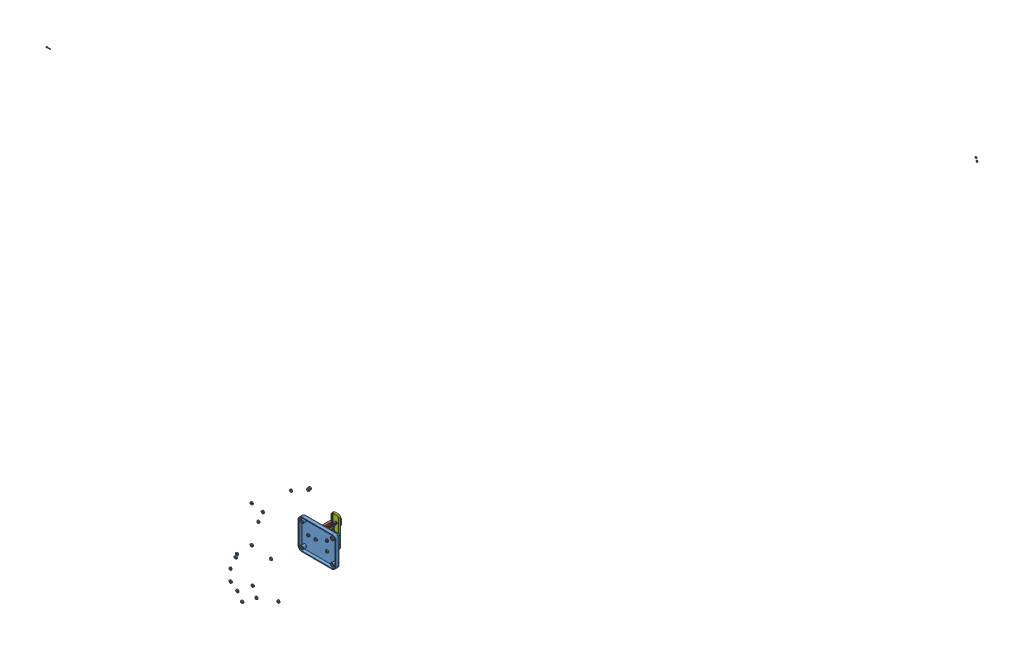
SolidWorks assembly motion_study, configuration Default. Lengths in mm.
Overall size (1399.7 805.72 1298.1).
38 component instances, 9 part files, 40 mates.
Components (placement in the parent):
- base-1: base [Default] at (50.4924 43.8567 70.47) size (100 80 10)
- bracket-1: bracket [Default] at (30.4924 43.8567 70.47) x (-1 0 0) z (0 0 -1) size (36 36 73)
- servo_mount-1: servo_mount [Default] at (52.4924 43.8567 70.47) x (1 0 0) z (0 1 0) size (30 30 36)
- socket head cap screw_ai-3: socket head cap screw_ai [HX-SHCS 0.112-40x0.375x0.375-N] at (20.4924 43.8567 64.6252) x (0 0 1) z (0.812322 -0.583209 0) size (12.37 4.65 4.65)
- socket head cap screw_ai-4: socket head cap screw_ai [HX-SHCS 0.112-40x0.375x0.375-N] at (40.4924 43.8567 64.6252) x (0 0 1) z (-0.967411 -0.25321 0) size (12.37 4.65 4.65)
- socket head cap screw_ai-18: socket head cap screw_ai [HX-SHCS 0.112-40x0.375x0.375-N] at (70.4924 56.3567 64.6252) x (0 0 1) z (-0.695922 0.718118 0) size (12.37 4.65 4.65)
- socket head cap screw_ai-19: socket head cap screw_ai [HX-SHCS 0.112-40x0.375x0.375-N] at (22.6476 43.6627 23.1238) x (1 0 0) z (0 0.590305 0.80718) size (12.37 4.65 4.65)
- socket head cap screw_ai-20: socket head cap screw_ai [HX-SHCS 0.112-40x0.375x0.375-N] at (70.4924 31.3567 64.6252) x (0 0 1) z (0.03914 0.999234 0) size (12.37 4.65 4.65)
- machine screw nut hex_ai-2: machine screw nut hex_ai [MSHXNUT 0.112-40-S-N] at (21.6751 -68.2967 155.3337) size (6.35 7.33 2.49)
- machine screw nut hex_ai-3: machine screw nut hex_ai [MSHXNUT 0.112-40-S-N] at (-36.4584 -88.814 155.5393) size (6.35 7.33 2.49)
- machine screw nut hex_ai-4: machine screw nut hex_ai [MSHXNUT 0.112-40-S-N] at (-64.4617 -107.1752 165.356) size (6.35 7.33 2.49)
- machine screw nut hex_ai-5: machine screw nut hex_ai [MSHXNUT 0.112-40-S-N] at (-92.7843 -103.8393 150.1747) size (6.35 7.33 2.49)
- machine screw nut hex_ai-6: machine screw nut hex_ai [MSHXNUT 0.112-40-S-N] at (-123.0762 -103.4925 137.6299) size (6.35 7.33 2.49)
- machine screw nut hex_ai-7: machine screw nut hex_ai [MSHXNUT 0.112-40-S-N] at (-142.6432 -93.4426 118.2638) size (6.35 7.33 2.49)
- machine screw nut hex_ai-8: machine screw nut hex_ai [MSHXNUT 0.112-40-S-N] at (-147.3644 -78.9178 99.7217) size (6.35 7.33 2.49)
- machine screw nut hex_ai-9: machine screw nut hex_ai [MSHXNUT 0.112-40-S-N] at (-149.2394 -74.9915 94.4694) size (6.35 7.33 2.49)
- machine screw nut hex_ai-11: machine screw nut hex_ai [MSHXNUT 0.112-40-S-N] at (-182.4764 -10.2892 22.3721) size (6.35 7.33 2.49)
- machine screw nut hex_ai-13: machine screw nut hex_ai [MSHXNUT 0.112-40-S-N] at (20.4924 43.8567 74.9592) size (6.35 7.33 2.49)
- machine screw nut hex_ai-17: machine screw nut hex_ai [MSHXNUT 0.112-40-S-N] at (70.4924 56.3567 74.9338) size (6.35 7.33 2.49)
- machine screw nut hex_ai-18: machine screw nut hex_ai [MSHXNUT 0.112-40-S-N] at (-74.3839 54.9241 -24.4269) size (6.35 7.33 2.49)
- machine screw nut hex_ai-19: machine screw nut hex_ai [MSHXNUT 0.112-40-S-N] at (40.4924 43.8567 74.9592) size (6.35 7.33 2.49)
- machine screw nut hex_ai-20: machine screw nut hex_ai [MSHXNUT 0.112-40-S-N] at (-75.8204 52.0566 -21.7162) size (6.35 7.33 2.49)
- machine screw nut hex_ai-21: machine screw nut hex_ai [MSHXNUT 0.112-40-S-N] at (70.4924 31.3567 74.9592) size (6.35 7.33 2.49)
- machine screw nut hex_ai-22: machine screw nut hex_ai [MSHXNUT 0.112-40-S-N] at (-115.6581 32.8101 -15.6303) size (6.35 7.33 2.49)
- machine screw nut hex_ai-23: machine screw nut hex_ai [MSHXNUT 0.112-40-S-N] at (-151.0091 -14.0767 23.9369) size (6.35 7.33 2.49)
- machine screw nut hex_ai-24: machine screw nut hex_ai [MSHXNUT 0.112-40-S-N] at (-146.959 -26.5776 39.89) size (6.35 7.33 2.49)
- machine screw nut hex_ai-25: machine screw nut hex_ai [MSHXNUT 0.112-40-S-N] at (-127.4649 -52.2459 77.1292) size (6.35 7.33 2.49)
- machine screw nut hex_ai-26: machine screw nut hex_ai [MSHXNUT 0.112-40-S-N] at (-63.8542 -83.0897 137.992) size (6.35 7.33 2.49)
- machine screw nut hex_ai-27: machine screw nut hex_ai [MSHXNUT 0.112-40-S-N] at (-60.5334 -42.4208 92.7075) size (6.35 7.33 2.49)
- Micro Servo FS90R Continuous-1: Micro Servo FS90R Continuous [Valor predeterminado] at (57.4924 43.8567 46.57) x (0 1 0) z (0 0 1) size (32 29 12)
- shelf-1: shelf [Default] at (43.4924 40.0088 25.6238) x (0 -1 0) z (0 0 -1) size (80 26 5)
- servo_arm-1: servo_arm [Default] at (44.9924 49.3667 36.1191) x (0 0.717335 -0.696728) z (-1 0 0) size (38 10 4)
- clip-2: clip [Default] at (25.4924 43.6627 23.1238) x (0 -1 0) z (1 0 0) size (10 7 8)
- socket head cap screw_ai-21: socket head cap screw_ai [HX-SHCS 0.06-80x0.375x0.375-N] at (-803.2469 693.6612 -53.4836) size (11.05 2.44 2.44)
- socket head cap screw_ai-22: socket head cap screw_ai [HX-SHCS 0.06-80x0.375x0.375-N] at (50.9684 57.4817 46.47) x (1 0 0) z (0 0.078665 0.996901) size (11.05 2.44 2.44)
- socket head cap screw_ai-23: socket head cap screw_ai [HX-SHCS 0.06-80x0.375x0.375-N] at (50.9684 30.2317 46.47) size (11.05 2.44 2.44)
- machine screw nut hex_ai-28: machine screw nut hex_ai [MSHXNUT 0.060-80-S-N] at (594.4756 589.4997 -1131.4765) size (3.96 4.58 1.27)
- machine screw nut hex_ai-29: machine screw nut hex_ai [MSHXNUT 0.060-80-S-N] at (592.2475 597.0474 -1131.1006) size (3.96 4.58 1.27)
Mates (geometry in assembly coordinates):
- Coincident1: coincident anti-aligned: plane of base-1 through (50.4924 43.8567 70.47) normal (0 0 -1); plane of bracket-1 through (30.4924 43.8567 70.47) normal (0 0 1)
- Coincident2: coincident anti-aligned: plane of base-1 through (50.4924 43.8567 70.47) normal (0 0 -1); plane of servo_mount-1 through (52.4924 61.8567 70.47) normal (0 0 1)
- Concentric2: concentric aligned: cylinder of servo_mount-1 through (70.4924 56.3567 82.47) axis (0 0 -1) radius 1.5; cylinder of socket head cap screw_ai-18 through (70.4924 56.3567 32.8752) axis (0 0 -1) radius 1.4224
- Concentric3: concentric aligned: cylinder of base-1 through (70.4924 56.3567 80.47) axis (0 0 -1) radius 1.5; cylinder of socket head cap screw_ai-18 through (70.4924 56.3567 32.8752) axis (0 0 -1) radius 1.4224
- Coincident3: coincident aligned: plane of servo_mount-1 through (52.4924 61.8567 67.47) normal (0 0 -1); circle of socket head cap screw_ai-18
- Coincident4: coincident aligned: plane of base-1 through (50.4924 43.8567 72.47) normal (0 0 1); circle of machine screw nut hex_ai-17
- Concentric5: concentric anti-aligned: cylinder of socket head cap screw_ai-18 through (70.4924 56.3567 32.8752) axis (0 0 -1) radius 1.4224; cylinder of machine screw nut hex_ai-17 through (70.4924 56.3567 72.4446) axis (0 0 1) radius 1.1303
- Concentric6: concentric aligned: cylinder of servo_mount-1 through (70.4924 31.3567 82.47) axis (0 0 -1) radius 1.5; cylinder of socket head cap screw_ai-20 through (70.4924 31.3567 32.8752) axis (0 0 -1) radius 1.4224
- Concentric7: concentric aligned: cylinder of base-1 through (70.4924 31.3567 80.47) axis (0 0 -1) radius 1.5; cylinder of socket head cap screw_ai-20 through (70.4924 31.3567 32.8752) axis (0 0 -1) radius 1.4224
- Coincident5: coincident anti-aligned: plane of servo_mount-1 through (52.4924 61.8567 67.47) normal (0 0 -1); plane of socket head cap screw_ai-20 through (72.8147 31.2657 67.47) normal (0 0 1)
- Coincident6: coincident anti-aligned: plane of base-1 through (50.4924 43.8567 72.47) normal (0 0 1); plane of machine screw nut hex_ai-21 through (64.1424 31.3567 72.47) normal (0 0 -1)
- Concentric8: concentric aligned: cylinder of socket head cap screw_ai-20 through (70.4924 31.3567 32.8752) axis (0 0 -1) radius 1.4224; circle of machine screw nut hex_ai-21
- Concentric9: concentric aligned: cylinder of bracket-1 through (40.4924 43.8567 70.47) axis (0 0 -1) radius 1.5; cylinder of socket head cap screw_ai-4 through (40.4924 43.8567 32.8752) axis (0 0 -1) radius 1.4224
- Concentric10: concentric aligned: cylinder of base-1 through (40.4924 43.8567 80.47) axis (0 0 -1) radius 1.5; cylinder of socket head cap screw_ai-4 through (40.4924 43.8567 32.8752) axis (0 0 -1) radius 1.4224
- Coincident7: coincident anti-aligned: plane of bracket-1 through (30.4924 43.8567 67.47) normal (0 0 -1); plane of socket head cap screw_ai-4 through (39.9039 46.105 67.47) normal (0 0 1)
- Concentric11: concentric aligned: cylinder of bracket-1 through (20.4924 43.8567 70.47) axis (0 0 -1) radius 1.5; cylinder of socket head cap screw_ai-3 through (20.4924 43.8567 32.8752) axis (0 0 -1) radius 1.4224
- Concentric12: concentric aligned: cylinder of base-1 through (20.4924 43.8567 80.47) axis (0 0 -1) radius 1.5; cylinder of socket head cap screw_ai-3 through (20.4924 43.8567 32.8752) axis (0 0 -1) radius 1.4224
- Coincident8: coincident anti-aligned: plane of bracket-1 through (30.4924 43.8567 67.47) normal (0 0 -1); plane of socket head cap screw_ai-3 through (19.1369 41.9687 67.47) normal (0 0 1)
- Coincident12: coincident anti-aligned: plane of base-1 through (50.4924 43.8567 72.47) normal (0 0 1); plane of machine screw nut hex_ai-13 through (14.1424 43.8567 72.47) normal (0 0 -1)
- Concentric14: concentric anti-aligned: cylinder of socket head cap screw_ai-3 through (20.4924 43.8567 32.8752) axis (0 0 -1) radius 1.4224; cylinder of machine screw nut hex_ai-13 through (20.4924 43.8567 72.47) axis (0 0 1) radius 1.1303
- Coincident13: coincident anti-aligned: plane of base-1 through (50.4924 43.8567 72.47) normal (0 0 1); circle of machine screw nut hex_ai-19
- Concentric15: concentric anti-aligned: cylinder of socket head cap screw_ai-4 through (40.4924 43.8567 32.8752) axis (0 0 -1) radius 1.4224; cylinder of machine screw nut hex_ai-19 through (40.4924 43.8567 72.47) axis (0 0 1) radius 1.1303
- Coincident14: coincident anti-aligned: plane of servo_mount-1 through (52.4924 55.1067 52.47) normal (0 0 -1); plane of Micro Servo FS90R Continuous-1 through (57.4924 43.8567 52.47) normal (0 0 1)
- Coincident15: coincident anti-aligned: plane of servo_mount-1 through (52.4924 55.1067 52.47) normal (0 -1 0); plane of Micro Servo FS90R Continuous-1 through (73.4924 55.1067 40.57) normal (0 1 0)
- Parallel2: parallel anti-aligned: plane of base-1 through (50.4924 43.8567 70.47) normal (0 0 -1); plane of Micro Servo FS90R Continuous-1 through (73.4924 32.6067 52.57) normal (0 0 1)
- Concentric16: concentric anti-aligned: cylinder of Micro Servo FS90R Continuous-1 through (44.4924 38.6067 46.57) axis (1 0 0) radius 2.25; cylinder of servo_arm-1 through (46.9924 38.6067 46.57) axis (-1 0 0) radius 2.25
- Coincident23: coincident anti-aligned: plane of Micro Servo FS90R Continuous-1 through (46.9924 38.6067 46.57) normal (-1 0 0); plane of servo_arm-1 through (46.9924 38.6067 46.57) normal (1 0 0)
- Coincident29: coincident anti-aligned: plane of shelf-1 through (27.4924 40.0088 25.6238) normal (-1 0 0); plane of clip-2 through (27.4924 43.6627 23.1238) normal (1 0 0)
- Coincident36: coincident anti-aligned: plane of shelf-1 through (43.4924 40.0088 20.6238) normal (0 0 -1); plane of clip-2 through (33.4924 46.8567 20.6238) normal (0 0 1)
- Coincident37: coincident anti-aligned: circle of shelf-1; circle of clip-2
- Coincident38: coincident anti-aligned: plane of bracket-1 through (97.4924 40.8567 42.47) normal (0 1 0); plane of clip-2 through (33.4924 40.8567 20.6238) normal (0 -1 0)
- Coincident39: coincident anti-aligned: plane of bracket-1 through (97.4924 46.8567 42.47) normal (0 -1 0); plane of clip-2 through (33.4924 46.8567 20.6238) normal (0 1 0)
- Coincident40: coincident anti-aligned: plane of bracket-1 through (27.4924 56.3567 -2.53) normal (-1 0 0); plane of clip-2 through (27.4924 43.6627 23.1238) normal (1 0 0)
- Concentric17: concentric anti-aligned: cylinder of socket head cap screw_ai-19 through (-9.1024 43.6627 23.1238) axis (-1 0 0) radius 1.4224; cylinder of clip-2 through (21.4924 43.6627 23.1238) axis (1 0 0) radius 1.425
- Coincident41: coincident anti-aligned: plane of socket head cap screw_ai-19 through (25.4924 45.5387 21.7519) normal (1 0 0); plane of clip-2 through (25.4924 43.6627 23.1238) normal (-1 0 0)
- Concentric18: concentric anti-aligned: cylinder of servo_mount-1 through (45.4924 57.4817 46.47) axis (1 0 0) radius 1; cylinder of socket head cap screw_ai-22 through (19.2184 57.4817 46.47) axis (-1 0 0) radius 0.762
- Coincident42: coincident anti-aligned: plane of servo_mount-1 through (52.4924 61.8567 40.47) normal (-1 0 0); plane of socket head cap screw_ai-22 through (52.4924 58.6971 46.3741) normal (1 0 0)
- Concentric19: concentric anti-aligned: cylinder of servo_mount-1 through (45.4924 30.2317 46.47) axis (1 0 0) radius 1; cylinder of socket head cap screw_ai-23 through (19.2184 30.2317 46.47) axis (-1 0 0) radius 0.762
- Coincident43: coincident anti-aligned: plane of servo_mount-1 through (52.4924 61.8567 40.47) normal (-1 0 0); plane of socket head cap screw_ai-23 through (52.4924 31.4509 46.47) normal (1 0 0)
- Coincident44: coincident anti-aligned: plane of servo_mount-1 through (55.4924 61.8567 40.47) normal (1 0 0); plane of Micro Servo FS90R Continuous-1 through (55.4924 57.4817 46.57) normal (-1 0 0)
